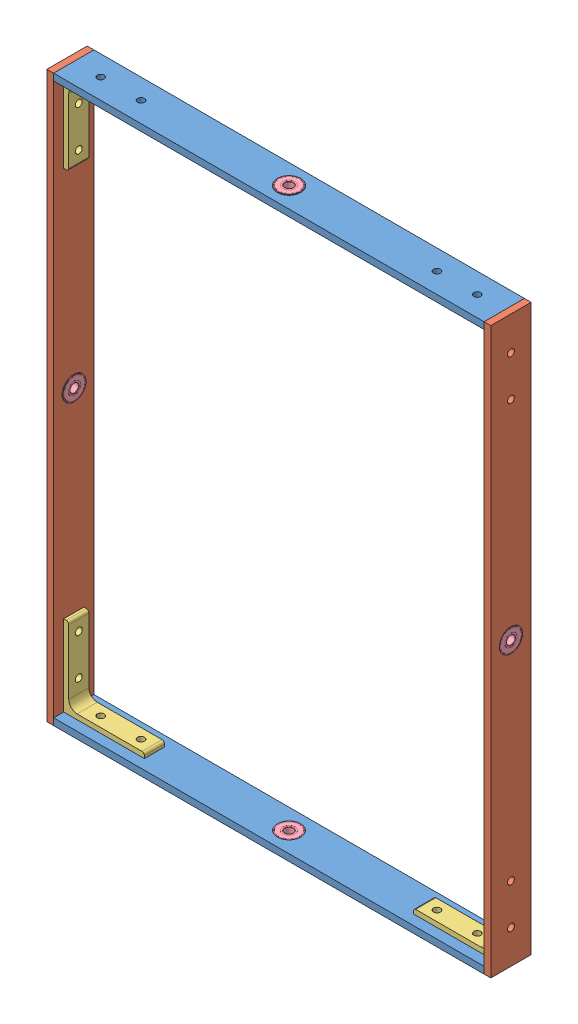
SolidWorks assembly InR_22mm, configuration Default. Lengths in mm.
Overall size (419.1 534.7 38.1).
12 component instances, 4 part files, 21 mates.
Components (placement in the parent):
- InR_S_22mm-1: InR_S_22mm [Default] at (38.1353 259.8741 -5.122) x (-1 0 0) z (0 0 1) size (406.4 6.35 38.1)
- InR_L_22mm-1: InR_L_22mm [Default] at (241.3353 -6.8259 -5.122) x (0 1 0) z (0 0 -1) size (533.4 6.35 38.1)
- InR_S_22mm-2: InR_S_22mm [Default] at (38.1353 -273.5259 -5.122) x (-1 0 0) z (0 0 -1) size (406.4 6.35 38.1)
- InR_L_22mm-2: InR_L_22mm [Default] at (-165.0647 -6.8259 -5.122) x (0 -1 0) z (0 0 -1) size (533.4 6.35 38.1)
- Stand_Bracket_3in-1: Stand_Bracket_3in [8982K254] at (-126.9647 215.4241 -5.122) x (0 1 0) z (0 0 -1) size (76.2 76.2 19.05)
- Stand_Bracket_3in-2: Stand_Bracket_3in [8982K254] at (-126.9647 -229.0759 -5.122) x (-1 0 0) z (0 0 -1) size (76.2 76.2 19.05)
- Stand_Bracket_3in-3: Stand_Bracket_3in [8982K254] at (203.2353 -229.0759 -5.122) size (76.2 76.2 19.05)
- Stand_Bracket_3in-4: Stand_Bracket_3in [8982K254] at (203.2353 215.4241 -5.122) x (0 1 0) z (0 0 1) size (76.2 76.2 19.05)
- 4668K133_Permanently Lubricated Stainless Steel Ball Bearing-1: 4668K133_Permanently Lubricated Stainless Steel Ball Bearing [4668K133] at (38.1353 -270.6759 -5.122) x (1 0 0) z (0 -1 0) size (22 22 7)
- 4668K133_Permanently Lubricated Stainless Steel Ball Bearing-2: 4668K133_Permanently Lubricated Stainless Steel Ball Bearing [4668K133] at (38.1353 257.0241 -5.122) x (-1 0 0) z (0 1 0) size (22 22 7)
- 4668K133_Permanently Lubricated Stainless Steel Ball Bearing-3: 4668K133_Permanently Lubricated Stainless Steel Ball Bearing [4668K133] at (-167.9147 -6.8259 -5.122) x (0 1 0) z (1 0 0) size (22 22 7)
- 4668K133_Permanently Lubricated Stainless Steel Ball Bearing-4: 4668K133_Permanently Lubricated Stainless Steel Ball Bearing [4668K133] at (244.1853 -6.8259 -5.122) x (0 -1 0) z (-1 0 0) size (22 22 7)
Mates (geometry in assembly coordinates):
- Coincident23: coincident anti-aligned: plane of InR_S_22mm-1 through (38.1353 253.5241 -5.122) normal (0 -1 0); plane of Stand_Bracket_3in-1 through (-165.0647 253.5241 -14.647) normal (0 1 0)
- Coincident24: coincident anti-aligned: plane of InR_L_22mm-2 through (-165.0647 -6.8259 -5.122) normal (1 0 0); plane of Stand_Bracket_3in-1 through (-165.0647 177.3241 -14.647) normal (-1 0 0)
- Coincident26: coincident anti-aligned: plane of InR_S_22mm-1 through (-165.0647 253.5241 13.928) normal (-1 0 0); plane of InR_L_22mm-2 through (-165.0647 -6.8259 -5.122) normal (1 0 0)
- Concentric1: concentric anti-aligned: cylinder of InR_L_22mm-2 through (-171.4147 228.1241 -5.122) axis (-1 0 0) radius 3.2639; cylinder of Stand_Bracket_3in-1 through (-160.3022 228.1241 -5.122) axis (1 0 0) radius 3.2639
- Concentric2: concentric aligned: cylinder of InR_S_22mm-1 through (-139.6647 253.5241 -5.122) axis (0 -1 0) radius 3.2639; cylinder of Stand_Bracket_3in-1 through (-139.6647 248.7616 -5.122) axis (0 -1 0) radius 3.2639
- Coincident27: coincident anti-aligned: plane of InR_L_22mm-2 through (-165.0647 -6.8259 -5.122) normal (1 0 0); plane of Stand_Bracket_3in-2 through (-165.0647 -267.1759 -14.647) normal (-1 0 0)
- Coincident28: coincident anti-aligned: plane of InR_S_22mm-2 through (38.1353 -267.1759 -5.122) normal (0 1 0); plane of Stand_Bracket_3in-2 through (-88.8647 -267.1759 -14.647) normal (0 -1 0)
- Concentric3: concentric aligned: cylinder of InR_S_22mm-2 through (-139.6647 -267.1759 -5.122) axis (0 1 0) radius 3.2639; cylinder of Stand_Bracket_3in-2 through (-139.6647 -262.4134 -5.122) axis (0 1 0) radius 3.2639
- Concentric4: concentric anti-aligned: cylinder of InR_L_22mm-2 through (-171.4147 -241.7759 -5.122) axis (-1 0 0) radius 3.2639; cylinder of Stand_Bracket_3in-2 through (-160.3022 -241.7759 -5.122) axis (1 0 0) radius 3.2639
- Coincident29: coincident anti-aligned: plane of InR_S_22mm-1 through (38.1353 253.5241 -5.122) normal (0 -1 0); plane of Stand_Bracket_3in-4 through (241.3353 253.5241 4.403) normal (0 1 0)
- Coincident30: coincident anti-aligned: plane of InR_L_22mm-1 through (241.3353 -6.8259 -5.122) normal (-1 0 0); plane of Stand_Bracket_3in-4 through (241.3353 177.3241 4.403) normal (1 0 0)
- Concentric5: concentric aligned: cylinder of InR_S_22mm-1 through (215.9353 253.5241 -5.122) axis (0 -1 0) radius 3.2639; cylinder of Stand_Bracket_3in-4 through (215.9353 248.7616 -5.122) axis (0 -1 0) radius 3.2639
- Concentric6: concentric anti-aligned: cylinder of InR_L_22mm-1 through (247.6853 228.1241 -5.122) axis (1 0 0) radius 3.2639; cylinder of Stand_Bracket_3in-4 through (236.5728 228.1241 -5.122) axis (-1 0 0) radius 3.2639
- Concentric7: concentric aligned: cylinder of InR_S_22mm-1 through (177.8353 253.5241 -5.122) axis (0 -1 0) radius 3.2639; cylinder of Stand_Bracket_3in-4 through (177.8353 248.7616 -5.122) axis (0 -1 0) radius 3.2639
- Concentric8: concentric anti-aligned: cylinder of InR_L_22mm-1 through (247.6853 -241.7759 -5.122) axis (1 0 0) radius 3.2639; cylinder of Stand_Bracket_3in-3 through (236.5728 -241.7759 -5.122) axis (-1 0 0) radius 3.2639
- Concentric9: concentric aligned: cylinder of InR_S_22mm-2 through (215.9353 -267.1759 -5.122) axis (0 1 0) radius 3.2639; cylinder of Stand_Bracket_3in-3 through (215.9353 -262.4134 -5.122) axis (0 1 0) radius 3.2639
- Coincident31: coincident anti-aligned: plane of InR_S_22mm-2 through (38.1353 -267.1759 -5.122) normal (0 1 0); plane of Stand_Bracket_3in-3 through (165.1353 -267.1759 4.403) normal (0 -1 0)
- Concentric10: concentric anti-aligned: cylinder of InR_S_22mm-2 through (38.1353 -274.7959 -5.122) axis (0 1 0) radius 11; cylinder of 4668K133_Permanently Lubricated Stainless Steel Ball Bearing-1 through (38.1353 -274.1759 -5.122) axis (0 -1 0) radius 11
- Coincident32: coincident aligned: plane of InR_S_22mm-2 through (38.1353 -267.1759 -5.122) normal (0 1 0); plane of 4668K133_Permanently Lubricated Stainless Steel Ball Bearing-1 through (38.1353 -267.1759 -5.122) normal (0 1 0)
- Concentric11: concentric anti-aligned: cylinder of InR_L_22mm-2 through (-163.7947 -6.8259 -5.122) axis (-1 0 0) radius 11; cylinder of 4668K133_Permanently Lubricated Stainless Steel Ball Bearing-3 through (-164.4147 -6.8259 -5.122) axis (1 0 0) radius 11
- Coincident33: coincident aligned: plane of InR_L_22mm-2 through (-171.4147 -6.8259 -5.122) normal (-1 0 0); circle of 4668K133_Permanently Lubricated Stainless Steel Ball Bearing-3
